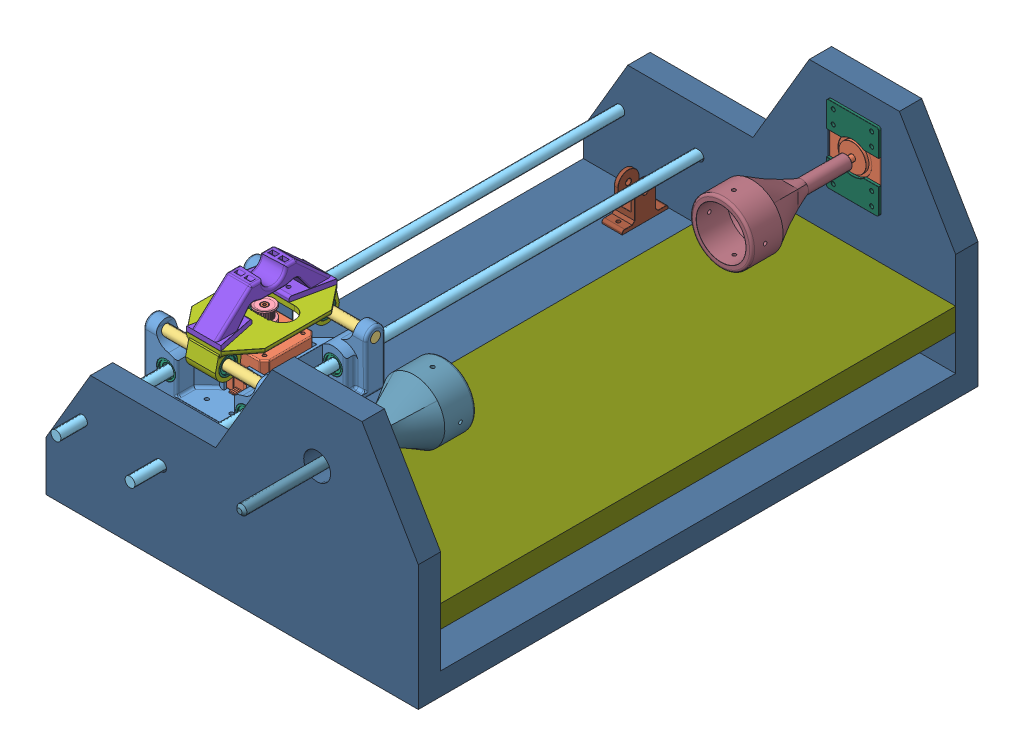
SolidWorks assembly Assembly, configuration Default. Lengths in mm.
Overall size (300 178.26 541.24).
30 component instances, 18 part files, 71 mates.
Components (placement in the parent):
- Cart-1: Cart [Default] at (-12.1645 37.455 139.1462) size (100.32 47.15 95)
- motor-1: motor [Default] at (37.8855 74.255 91.5962) x (-1 0 0) z (0 0 -1) size (42.3 52.83 47.3)
- Part8^Assembly-1: Part8^Assembly [Default] at origin (virtual)
- Short rod-4: Short rod [Default] at (87.8355 76.655 52.0957) x (0 0.266218 -0.963913) z (0 0.963913 0.266218) size (8 100 8)
- motor sprocket-1: motor sprocket [Default] at (37.8871 86.866 89.0962) x (0 -1 0) z (1 0 0.000652) size (16.47 16 16)
- Part3^Assembly-1: Part3^Assembly [Default] at origin (virtual)
- Short rod-5: Short rod [Default] at (87.8355 76.655 131.1966) x (0 -0.051428 0.998677) z (0 -0.998677 -0.051428) size (8 100 8)
- Long Rod-1: Long Rod [Default] at (7.4027 56.3299 -270.7782) x (-0.784758 -0.619802 0) z (-0.619802 0.784758 0) size (8 500 8)
- Long Rod-2: Long Rod [Default] at (69.7105 56.455 -268.163) x (0.153298 0.98818 0) z (0.98818 -0.153298 0) size (8 500 8)
- Linear Bearing-1: Linear Bearing [Default] at (69.7105 56.455 115.2534) x (0.841336 -0.540513 0) z (-0.540513 -0.841336 0) size (15 24 15)
- Linear Bearing-2: Linear Bearing [Default] at (5.9605 56.455 44.0408) x (0.959166 0.282842 0) z (0.282842 -0.959166 0) size (15 24 15)
- Linear Bearing-3: Linear Bearing [Default] at (69.7105 56.455 44.1199) x (-0.499292 0.866434 0) z (0.866434 0.499292 0) size (15 24 15)
- Linear Bearing-4: Linear Bearing [Default] at (5.9605 56.455 114.8702) x (0.50045 -0.865766 0) z (-0.865766 -0.50045 0) size (15 24 15)
- Linear Bearing-5: Linear Bearing [Default] at (48.2114 76.655 52.0346) x (0 -0.41872 0.908116) z (0 -0.908116 -0.41872) size (15 24 15)
- Linear Bearing-6: Linear Bearing [Default] at (24.2114 76.655 131.1966) x (0 0.771376 0.63638) z (0 0.63638 -0.771376) size (15 24 15)
- solder cart 1-4: solder cart 1 [Default] at (40.2029 86.655 91.6156) size (58.85 24.53 99.91)
- solder cart-2: solder cart [Default] at (32.9065 90.655 98.7979) size (28.41 29.51 97.1)
- belt fixer-1: belt fixer [Default] at (37.8355 36.705 128.1046) x (-1 0 0) z (0 0 1) size (31.17 2.25 11.61)
- box-1: box [Default] at (278.0427 -10.1701 207.8607) x (0 0 -1) z (1 0 0) size (451 178.26 300)
- belt fixer-2: belt fixer [Default] at (37.8355 36.705 55.1877) x (1 0 0) z (0 0 -1) size (31.17 2.25 11.61)
- motor-2: motor [Default] at (53.7433 28.7799 168.9107) x (0 0 1) z (0 -1 0) size (42.3 52.83 47.3)
- motor sprocket-2: motor sprocket [Default] at (41.1709 28.7799 166.4107) x (1 0 0) z (0 1 0) size (16.47 16 16)
- pulley-1: pulley [Default] at (33.717 7.8299 -205.8817) x (0 0 1) z (-1 0 0) size (37 29.65 16.5)
- motor holder-1: motor holder [Default] at (53.7433 -2.2201 168.961) x (0 0 -1) z (0 1 0) size (42.3 26.22 11.15)
- candle motor side-1: candle motor side [Default] at (196.8427 118.8299 -217.8089) x (0.999957 0.009274 0) z (0.009274 -0.999957 0) size (50.1 100.5 50.1)
- candle-1: candle [Default] at (196.5427 118.8299 270.4574) x (-0.083266 -0.996527 0) z (0.996527 -0.083266 0) size (50.1 165.5 50.1)
- motor-3: motor [Default] at (196.8427 118.8299 -225.1393) x (0 -1 0) z (-1 0 0) size (42.3 52.83 47.3)
- motor holder1-1: motor holder1 [Default] at (196.8929 87.8299 -225.1393) x (-1 0 0) z (0 1 0) size (42.3 2 21.15)
- motor holder1-2: motor holder1 [Default] at (196.8427 149.7796 -225.1393) x (1 0 0) z (0 -1 0) size (42.3 2 21.15)
- Support-1: Support [Default] at (278.0427 36.8299 189.8607) x (0 0 -1) z (1 0 0) size (415 18 163.3)
Mates (geometry in assembly coordinates):
- Coincident1: coincident anti-aligned: plane of Cart-1 through (-12.1645 41.455 139.1462) normal (0 1 0); plane of motor-1 through (37.8855 41.455 91.5962) normal (0 -1 0)
- Concentric1: concentric aligned: cylinder of Cart-1 through (87.8355 76.655 131.1966) axis (1 0 0) radius 4; cylinder of ? through (-7.7367 76.655 131.1966) axis (1 0 0) radius 4
- Concentric2: concentric anti-aligned: cylinder of Cart-1 through (-2.1645 76.655 52.0957) axis (-1 0 0) radius 4; cylinder of Short rod-4 through (-12.1645 76.655 52.0957) axis (1 0 0) radius 4
- Concentric3: concentric anti-aligned: cylinder of motor-1 through (37.8855 94.255 91.5962) axis (0 -1 0) radius 2.5; cylinder of motor sprocket-1 through (37.8855 94.2937 91.5962) axis (0 1 0) radius 2.5
- Concentric6: concentric aligned: cylinder of Cart-1 through (77.8355 76.655 131.1966) axis (1 0 0) radius 4; cylinder of Short rod-5 through (-12.1645 76.655 131.1966) axis (1 0 0) radius 4
- Concentric7: concentric aligned: cylinder of Cart-1 through (5.9605 56.455 115.0462) axis (0 0 1) radius 7.7; cylinder of ? through (5.9605 56.455 112.1662) axis (0 0 1) radius 7.5
- Concentric10: concentric aligned: cylinder of Cart-1 through (69.7105 56.455 115.0462) axis (0 0 1) radius 7.7; cylinder of ? through (69.7105 56.455 112.1641) axis (0 0 1) radius 7.5
- Concentric12: concentric anti-aligned: cylinder of Cart-1 through (69.7105 56.455 68.2462) axis (0 0 -1) radius 7.7; cylinder of ? through (69.7105 56.455 37.7561) axis (0 0 1) radius 7.5
- Concentric13: concentric anti-aligned: cylinder of Cart-1 through (5.9605 56.455 68.2462) axis (0 0 -1) radius 7.7; cylinder of ? through (5.9605 56.455 37.934) axis (0 0 1) radius 7.5
- Concentric15: concentric anti-aligned: cylinder of ? through (69.7105 56.455 107.8141) axis (0 0 1) radius 4; cylinder of Long Rod-2 through (69.7105 56.455 247.5466) axis (0 0 -1) radius 4
- Concentric16: concentric anti-aligned: cylinder of Cart-1 through (69.7105 56.455 115.0462) axis (0 0 1) radius 7.6; cylinder of Linear Bearing-1 through (69.7105 56.455 139.2534) axis (0 0 -1) radius 7.5
- Concentric17: concentric aligned: cylinder of Cart-1 through (5.9605 56.455 68.2462) axis (0 0 -1) radius 7.6; cylinder of Linear Bearing-2 through (5.9605 56.455 68.0408) axis (0 0 -1) radius 7.5
- Concentric19: concentric aligned: cylinder of Cart-1 through (69.7105 56.455 68.2462) axis (0 0 -1) radius 7.6; cylinder of Linear Bearing-3 through (69.7105 56.455 68.1199) axis (0 0 -1) radius 7.5
- Concentric20: concentric anti-aligned: cylinder of Cart-1 through (5.9605 56.455 115.0462) axis (0 0 1) radius 7.6; cylinder of Linear Bearing-4 through (5.9605 56.455 138.8702) axis (0 0 -1) radius 7.5
- Concentric21: concentric anti-aligned: cylinder of Long Rod-2 through (69.7105 56.455 231.837) axis (0 0 -1) radius 4; cylinder of Linear Bearing-1 through (69.7105 56.455 116.2534) axis (0 0 1) radius 4
- Parallel6: parallel aligned: cylinder of ? through (-108.844 91.3324 208.9861) axis (-1 0 0) radius 7.7; cylinder of Linear Bearing-6 through (43.0123 76.655 131.1966) axis (-1 0 0) radius 7.5
- Coincident21: coincident aligned: plane of ? through (-108.844 76.8823 131.0404) normal (1 0 0); plane of Linear Bearing-5 through (-108.844 76.655 131.1966) normal (1 0 0)
- Coincident22: coincident aligned: plane of ? through (-108.844 91.6009 209.0487) normal (1 0 0); plane of Linear Bearing-6 through (-108.844 91.3324 208.9861) normal (1 0 0)
- Concentric30: concentric aligned: cylinder of ? through (-108.844 91.3324 208.9861) axis (-1 0 0) radius 7.7; cylinder of Linear Bearing-6 through (-108.844 91.3324 208.9861) axis (-1 0 0) radius 7.5
- Concentric31: concentric anti-aligned: cylinder of Linear Bearing-6 through (38.7621 76.655 131.1966) axis (-1 0 0) radius 7.5; cylinder of ? through (14.7621 76.655 131.1966) axis (1 0 0) radius 7.7
- Coincident23: coincident aligned: plane of Linear Bearing-6 through (38.7621 76.655 131.1966) normal (1 0 0); plane of ? through (38.7621 76.4033 131.3093) normal (1 0 0)
- Concentric32: concentric aligned: cylinder of Linear Bearing-5 through (14.7621 76.242 52.0357) axis (1 0 0) radius 7.5; cylinder of ? through (14.7621 76.242 52.0357) axis (1 0 0) radius 7.7
- Coincident24: coincident aligned: plane of Linear Bearing-5 through (38.7621 76.242 52.0357) normal (1 0 0); plane of ? through (38.7621 75.9891 51.9257) normal (1 0 0)
- Concentric36: concentric aligned: cylinder of Short rod-5 through (-12.1645 76.655 131.1966) axis (1 0 0) radius 4; cylinder of Linear Bearing-6 through (25.2114 76.655 131.1966) axis (1 0 0) radius 4
- Concentric42: concentric anti-aligned: cylinder of Linear Bearing-6 through (-43.342 76.655 131.1966) axis (-1 0 0) radius 7.5; cylinder of ? through (-307.0859 76.655 131.1966) axis (1 0 0) radius 7.7
- Coincident26: coincident aligned: plane of Linear Bearing-6 through (48.2114 76.655 131.1966) normal (1 0 0); plane of solder cart 1-4 through (48.2114 76.4027 131.308) normal (1 0 0)
- Parallel9: parallel anti-aligned: plane of motor-1 through (37.8855 74.255 91.5962) normal (0 1 0); plane of solder cart 1-4 through (40.2029 86.655 91.6156) normal (0 -1 0)
- Coincident32: coincident anti-aligned: line of solder cart 1-4 through (54.7242 0.1 39.4861) axis (-1 0 0); line of ? through (-11.0626 0.1 39.4861) axis (1 0 0)
- Concentric50: concentric aligned: cylinder of solder cart 1-4 through (35.6325 90.655 69.9473) axis (0 -1 0) radius 1.5; cylinder of solder cart-2 through (35.6325 94.655 69.9473) axis (0 -1 0) radius 1.5
- Coincident34: coincident anti-aligned: plane of solder cart 1-4 through (40.2029 90.655 91.6156) normal (0 1 0); plane of solder cart-2 through (32.9065 90.655 98.7979) normal (0 -1 0)
- Concentric51: concentric anti-aligned: cylinder of Cart-1 through (47.8355 41.455 128.1046) axis (0 -1 0) radius 1.55; cylinder of belt fixer-1 through (47.8355 35.205 128.1046) axis (0 1 0) radius 1.6
- Coincident35: coincident anti-aligned: plane of Cart-1 through (-12.1645 37.455 139.1462) normal (0 -1 0); plane of belt fixer-1 through (37.8355 37.455 128.1046) normal (0 1 0)
- Concentric52: concentric aligned: cylinder of Linear Bearing-5 through (24.2114 76.655 52.0346) axis (1 0 0) radius 7.5; cylinder of solder cart 1-4 through (24.2114 76.655 52.0346) axis (1 0 0) radius 7.6
- Concentric53: concentric anti-aligned: cylinder of Linear Bearing-6 through (48.2114 76.655 131.1966) axis (-1 0 0) radius 7.5; cylinder of solder cart 1-4 through (24.2114 76.655 131.1966) axis (1 0 0) radius 7.6
- Coincident36: coincident aligned: plane of Linear Bearing-5 through (48.2114 76.655 52.0346) normal (1 0 0); plane of solder cart 1-4 through (48.2114 76.4027 51.9233) normal (1 0 0)
- Concentric54: concentric anti-aligned: cylinder of Cart-1 through (27.8355 41.455 55.1877) axis (0 -1 0) radius 1.55; cylinder of belt fixer-2 through (27.8355 35.205 55.1877) axis (0 1 0) radius 1.6
- Coincident39: coincident anti-aligned: plane of Cart-1 through (-12.1645 37.455 139.1462) normal (0 -1 0); plane of belt fixer-2 through (37.8355 37.455 55.1877) normal (0 1 0)
- Concentric55: concentric aligned: cylinder of solder cart 1-4 through (35.6325 90.655 113.284) axis (0 -1 0) radius 1.5; cylinder of solder cart-2 through (35.6325 94.655 113.284) axis (0 -1 0) radius 1.5
- Coincident40: coincident aligned: plane of Cart-1 through (-12.1645 41.455 139.1462) normal (-1 0 0); plane of Short rod-4 through (-12.1645 76.655 52.0957) normal (-1 0 0)
- Coincident41: coincident aligned: plane of Cart-1 through (-12.1645 41.455 139.1462) normal (-1 0 0); plane of Short rod-5 through (-12.1645 76.655 131.1966) normal (-1 0 0)
- Concentric56: concentric anti-aligned: cylinder of motor-2 through (33.7433 28.7799 168.9107) axis (1 0 0) radius 2.5; cylinder of motor sprocket-2 through (33.7433 28.7799 168.9107) axis (-1 0 0) radius 2.5
- Coincident42: coincident aligned: plane of motor-2 through (33.7433 28.7799 168.9107) normal (-1 0 0); plane of motor sprocket-2 through (33.7433 28.7799 166.4107) normal (-1 0 0)
- Coincident43: coincident anti-aligned: plane of box-1 through (278.0427 7.8299 207.8607) normal (0 1 0); plane of motor-2 through (53.7433 7.8299 168.9107) normal (0 -1 0)
- Coincident44: coincident anti-aligned: plane of box-1 through (278.0427 -10.1701 189.8607) normal (0 0 -1); plane of motor-2 through (53.7433 28.7799 189.8607) normal (0 0 1)
- Concentric59: concentric aligned: cylinder of motor sprocket-2 through (33.7433 28.7799 168.9107) axis (-1 0 0) radius 5.35; cylinder of ? through (40.795 28.7799 168.9107) axis (-1 0 0) radius 7.8076
- Coincident48: coincident anti-aligned: plane of box-1 through (278.0427 7.8299 207.8607) normal (0 1 0); plane of pulley-1 through (30.717 7.8299 -197.3817) normal (0 -1 0)
- Concentric60: concentric anti-aligned: cylinder of motor-2 through (86.5433 13.2799 153.461) axis (-1 0 0) radius 1.25; cylinder of motor holder-1 through (50.7433 13.2799 153.461) axis (1 0 0) radius 1.5
- Coincident49: coincident anti-aligned: plane of motor-2 through (53.7433 28.7799 168.9107) normal (-1 0 0); plane of motor holder-1 through (53.7433 -2.2201 168.961) normal (1 0 0)
- Coincident50: coincident anti-aligned: plane of Cart-1 through (-12.1645 37.455 139.1462) normal (0 -1 0); plane of ? through (40.795 37.455 168.8699) normal (0 1 0)
- Coincident51: coincident anti-aligned: circle of solder cart-2; plane of ? through (43.7323 127.3668 91.5556) normal (-1 0 0)
- Concentric64: concentric anti-aligned: circle of ?; circle of candle motor side-1
- Concentric66: concentric aligned: cylinder of pulley-1 through (30.717 28.9799 -205.8817) axis (1 0 0) radius 2.25; cylinder of ? through (27.7637 28.9799 -205.8817) axis (1 0 0) radius 2.25
- Concentric68: concentric aligned: cylinder of candle motor side-1 through (196.8427 118.8299 -197.8089) axis (0 0 -1) radius 2.5; cylinder of motor-3 through (196.8427 118.8299 -205.1393) axis (0 0 -1) radius 2.5
- Coincident52: coincident aligned: plane of box-1 through (278.0427 -10.1701 -225.1393) normal (0 0 1); plane of motor-3 through (196.8427 118.8299 -225.1393) normal (0 0 1)
- Coincident53: coincident anti-aligned: plane of box-1 through (278.0427 -10.1701 -225.1393) normal (0 0 1); plane of motor holder1-1 through (196.8929 121.152 -225.1393) normal (0 0 -1)
- Concentric70: concentric anti-aligned: circle of motor-3; cylinder of motor holder1-1 through (212.3427 103.3299 -223.1393) axis (0 0 -1) radius 1.5
- Coincident54: coincident anti-aligned: plane of box-1 through (278.0427 -10.1701 -225.1393) normal (0 0 1); plane of motor holder1-2 through (196.8427 116.4575 -225.1393) normal (0 0 -1)
- Concentric71: concentric aligned: circle of motor-3; cylinder of motor holder1-2 through (212.3427 134.2796 -223.1393) axis (0 0 -1) radius 1.5
- Concentric72: concentric aligned: cylinder of box-1 through (196.5427 118.8299 189.8607) axis (0 0 1) radius 10.85; cylinder of candle-1 through (196.5427 118.8299 185.4574) axis (0 0 1) radius 3.98
- Coincident57: coincident anti-aligned: plane of box-1 through (278.0427 -10.1701 189.8607) normal (0 0 -1); plane of Support-1 through (278.0427 54.8299 189.8607) normal (0 0 1)
- Coincident58: coincident aligned: plane of box-1 through (278.0427 7.8299 207.8607) normal (1 0 0); plane of Support-1 through (278.0427 54.8299 189.8607) normal (1 0 0)
- Coincident59: coincident aligned: plane of box-1 through (-21.9573 7.8299 207.8607) normal (0 0 1); plane of ? through (196.5427 118.8299 207.8607) normal (0 0 1)
- Concentric73: concentric anti-aligned: circle of candle-1; circle of ?
- Coincident60: coincident aligned: plane of box-1 through (278.0427 -10.1701 189.8607) normal (0 0 -1); plane of ? through (196.5427 118.8299 189.8607) normal (0 0 -1)
- Coincident61: coincident aligned: circle of box-1; circle of ?
- Concentric75: concentric aligned: cylinder of ? through (27.7637 28.9799 -205.8817) axis (1 0 0) radius 2.25; cylinder of ? through (33.2511 28.9799 -205.8817) axis (1 0 0) radius 4
- Tangent1: tangent: curve of candle motor side-1; circle of ?
- Coincident63: coincident anti-aligned: plane of box-1 through (217.7927 140.0799 -225.1393) normal (-1 0 0); plane of motor-3 through (217.7927 118.8299 -225.1393) normal (1 0 0)
- Concentric76: concentric anti-aligned: circle of Long Rod-1; circle of box-1
- Coincident64: coincident anti-aligned: plane of Cart-1 through (58.8355 66.455 70.6462) normal (-1 0 0); plane of motor-1 through (58.8355 74.255 91.5962) normal (1 0 0)
- Coincident65: coincident anti-aligned: plane of Cart-1 through (58.8355 66.455 70.6462) normal (0 0 1); plane of motor-1 through (37.8855 74.255 70.6462) normal (0 0 -1)
